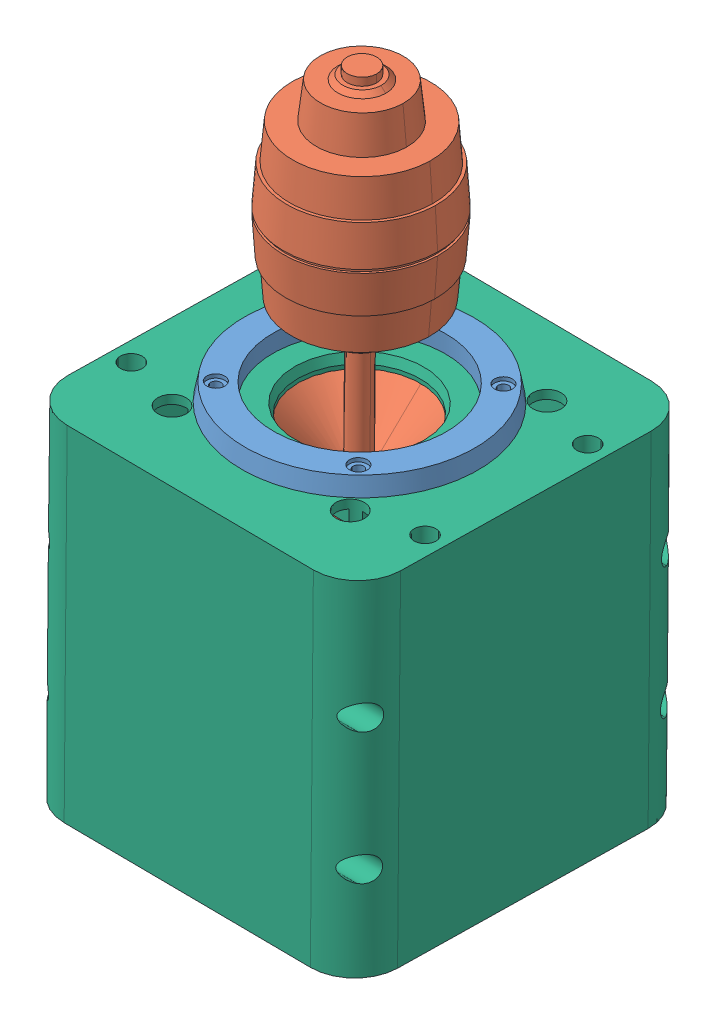
SolidWorks assembly Joystick control, configuration Default. Lengths in mm.
Overall size (77.67 146.17 78.62).
90 component instances, 26 part files, 9 mates.
Components (placement in the parent):
- D400B-M4-10KB 3-Axis Joystick with Button.STEP-1: D400B-M4-10KB 3-Axis Joystick with Button.STEP [Default] at (42.4495 -65.9811 -23.915) x (0.999962 0.000076 0.008726) z (-0.008727 0.008726 0.999924) size (76.37 95.5 76.37)
  - Mount Ring^D400B-M4-10KB 3-Axis Joystick with Button.STEP-1: Mount Ring^D400B-M4-10KB 3-Axis Joystick with Button.STEP [Default] at (0 28.75 0) x (0.707107 0 0.707107) z (-0.707107 0 0.707107) size (54 4 54)
  - Main^D400B-M4-10KB 3-Axis Joystick with Button.STEP-1: Main^D400B-M4-10KB 3-Axis Joystick with Button.STEP [Default] at origin size (59.55 95.5 49.55)
  - Seal^D400B-M4-10KB 3-Axis Joystick with Button.STEP-1: Seal^D400B-M4-10KB 3-Axis Joystick with Button.STEP [Default] at (0 25.75 0) x (0.707107 0 0.707107) z (-0.707107 0 0.707107) size (48.47 4 48.47) (hidden)
- remote_pcb.step-1: remote_pcb.step [Default] at (-56.1244 -87.3851 -127.4214) x (0.999962 0.000076 0.008726) z (0 0.999962 -0.008727) size (47.38 49.95 11.94)
  - PinHeader_1x04_P2.54mm_Vertical.step-1: PinHeader_1x04_P2.54mm_Vertical.step [Default] at (114.8 -120.23 1.63) x (-1 0 0) z (0 0 1) size (2.54 10.16 11.54)
    - SOLID.step-1: SOLID.step [Default] at origin size (2.54 10.16 11.54)
  - R_0402_1005Metric.step-1: R_0402_1005Metric.step [Default] at (89.4 -92.15 1.63) x (0 -1 0) z (0 0 1) size (1 0.5 0.35)
    - SOLID-0.step-1: SOLID-0.step [Default] at origin size (1 0.5 0.35)
  - JST_PH_S3B-PH-K_1x03_P2.00mm_Horizontal.step-1: JST_PH_S3B-PH-K_1x03_P2.00mm_Horizontal.step [Default] at (83.25 -107.15 1.63) x (0 -1 0) z (0 0 1) size (7.9 7.6 8.25)
    - SOLID-1.step-1: SOLID-1.step [Default] at origin size (7.9 7.6 8.25)
  - PinHeader_1x03_P2.54mm_Vertical.step-1: PinHeader_1x03_P2.54mm_Vertical.step [Default] at (92 -90.025 1.63) size (2.54 7.62 11.54)
    - SOLID-2.step-1: SOLID-2.step [Default] at origin size (2.54 7.62 11.54)
  - C_0402_1005Metric.step-1: C_0402_1005Metric.step [Default] at (105.05 -110.05 1.63) x (-1 0 0) z (0 0 1) size (1 0.5 0.5)
    - SOLID-3.step-1: SOLID-3.step [Default] at origin size (1 0.5 0.5)
  - R_0402_1005Metric.step-2: R_0402_1005Metric.step [Default] at (112.1 -90.4 1.63) x (0 1 0) z (0 0 1) size (1 0.5 0.35)
    - SOLID-0.step-1: SOLID-0.step [Default] at origin size (1 0.5 0.35)
  - PinHeader_1x04_P2.54mm_Vertical.step-2: PinHeader_1x04_P2.54mm_Vertical.step [Default] at (120.65 -120.28 1.63) x (-1 0 0) z (0 0 1) size (2.54 10.16 11.54)
    - SOLID.step-1: SOLID.step [Default] at origin size (2.54 10.16 11.54)
  - PinHeader_1x08_P2.54mm_Vertical.step-1: PinHeader_1x08_P2.54mm_Vertical.step [Default] at (105.275 -79.85 1.63) x (0 -1 0) z (0 0 1) size (2.54 20.32 11.54)
    - SOLID-4.step-1: SOLID-4.step [Default] at origin size (2.54 20.32 11.54)
  - L_1206_3216Metric.step-1: L_1206_3216Metric.step [Default] at (88.65 -97.75 1.63) x (0 1 0) z (0 0 1) size (3.2 1.6 1.6)
    - SOLID-5.step-1: SOLID-5.step [Default] at origin size (3.2 1.6 1.6)
  - R_0402_1005Metric.step-3: R_0402_1005Metric.step [Default] at (111.31 -107.5 1.63) x (0 -1 0) z (0 0 1) size (1 0.5 0.35)
    - SOLID-0.step-1: SOLID-0.step [Default] at origin size (1 0.5 0.35)
  - R_0402_1005Metric.step-4: R_0402_1005Metric.step [Default] at (90.81 -120.505 1.63) size (1 0.5 0.35)
    - SOLID-0.step-1: SOLID-0.step [Default] at origin size (1 0.5 0.35)
  - SW_CuK_JS202011AQN_DPDT_Angled.step-1: SW_CuK_JS202011AQN_DPDT_Angled.step [Default] at (118.175 -91.2005 1.63) x (0 1 0) z (0 0 1) size (9 5.6 6.5)
    - SOLID-6.step-1: SOLID-6.step [Default] at origin size (9 5.6 6.5)
  - SOT-23-6.step-1: SOT-23-6.step [Default] at (110.5 -86.85 1.63) size (2.8 2.9 1.55)
    - SOLID-7.step-1: SOLID-7.step [Default] at origin size (2.8 2.9 1.55)
  - C_1210_3225Metric.step-1: C_1210_3225Metric.step [Default] at (114.85 -89.35 1.63) x (0 -1 0) z (0 0 1) size (3.2 2.5 2.5)
    - SOLID-8.step-1: SOLID-8.step [Default] at origin size (3.2 2.5 2.5)
  - PinHeader_1x08_P2.54mm_Vertical.step-2: PinHeader_1x08_P2.54mm_Vertical.step [Default] at (96.02 -125.75 1.63) x (0 1 0) z (0 0 1) size (2.54 20.32 11.54)
    - SOLID-4.step-1: SOLID-4.step [Default] at origin size (2.54 20.32 11.54)
  - C_0402_1005Metric.step-2: C_0402_1005Metric.step [Default] at (90.2 -105.5 1.63) x (-1 0 0) z (0 0 1) size (1 0.5 0.5)
    - SOLID-3.step-1: SOLID-3.step [Default] at origin size (1 0.5 0.5)
  - C_0402_1005Metric.step-3: C_0402_1005Metric.step [Default] at (94.9 -105.2 1.63) x (0 -1 0) z (0 0 1) size (1 0.5 0.5)
    - SOLID-3.step-1: SOLID-3.step [Default] at origin size (1 0.5 0.5)
  - Crystal_SMD_3225-4Pin_3.2x2.5mm.step-1: Crystal_SMD_3225-4Pin_3.2x2.5mm.step [Default] at (92.2 -102.75 1.63) x (0 1 0) z (0 0 1) size (3.2 2.5 0.64)
    - SOLID-9.step-1: SOLID-9.step [Default] at origin size (3.2 2.5 0.64)
  - JST_PH_S2B-PH-K_1x02_P2.00mm_Horizontal.step-1: JST_PH_S2B-PH-K_1x02_P2.00mm_Horizontal.step [Default] at (83.3 -117.6 1.63) x (0 -1 0) z (0 0 1) size (5.9 7.6 8.25)
    - SOLID-10.step-1: SOLID-10.step [Default] at origin size (5.9 7.6 8.25)
  - L_Coilcraft_XAL5020-XXX.step-1: L_Coilcraft_XAL5020-XXX.step [Default] at (112.75 -81.2 1.63) x (-1 0 0) z (0 0 1) size (5.48 5.68 2)
    - COMPOUND.step-1: COMPOUND.step [Default] at origin size (5.48 5.68 2)
  - C_0402_1005Metric.step-4: C_0402_1005Metric.step [Default] at (107.5 -101.25 1.63) x (0 -1 0) z (0 0 1) size (1 0.5 0.5)
    - SOLID-3.step-1: SOLID-3.step [Default] at origin size (1 0.5 0.5)
  - LQFP-48_7x7mm_P0.5mm.step-1: LQFP-48_7x7mm_P0.5mm.step [Default] at (101.25 -104.25 1.63) size (9 9 1.5)
    - SOLID-11.step-1: SOLID-11.step [Default] at origin size (9 9 1.5)
  - R_0402_1005Metric.step-5: R_0402_1005Metric.step [Default] at (111.85 -104.2 1.63) x (0 -1 0) z (0 0 1) size (1 0.5 0.35)
    - SOLID-0.step-1: SOLID-0.step [Default] at origin size (1 0.5 0.35)
  - R_0402_1005Metric.step-6: R_0402_1005Metric.step [Default] at (111.31 -102 1.63) x (0 1 0) z (0 0 1) size (1 0.5 0.35)
    - SOLID-0.step-1: SOLID-0.step [Default] at origin size (1 0.5 0.35)
  - C_0402_1005Metric.step-5: C_0402_1005Metric.step [Default] at (93.6 -107.15 1.63) x (0 1 0) z (0 0 1) size (1 0.5 0.5)
    - SOLID-3.step-1: SOLID-3.step [Default] at origin size (1 0.5 0.5)
  - C_0402_1005Metric.step-6: C_0402_1005Metric.step [Default] at (96.25 -100.25 1.63) x (-1 0 0) z (0 0 1) size (1 0.5 0.5)
    - SOLID-3.step-1: SOLID-3.step [Default] at origin size (1 0.5 0.5)
  - C_0402_1005Metric.step-7: C_0402_1005Metric.step [Default] at (91.5 -99.75 1.63) size (1 0.5 0.5)
    - SOLID-3.step-1: SOLID-3.step [Default] at origin size (1 0.5 0.5)
  - JST_PH_S3B-PH-K_1x03_P2.00mm_Horizontal.step-2: JST_PH_S3B-PH-K_1x03_P2.00mm_Horizontal.step [Default] at (83.25 -96.65 1.63) x (0 -1 0) z (0 0 1) size (7.9 7.6 8.25)
    - SOLID-1.step-1: SOLID-1.step [Default] at origin size (7.9 7.6 8.25)
  - C_0402_1005Metric.step-8: C_0402_1005Metric.step [Default] at (89.7 -101.75 1.63) x (0 -1 0) z (0 0 1) size (1 0.5 0.5)
    - SOLID-3.step-1: SOLID-3.step [Default] at origin size (1 0.5 0.5)
  - JST_PH_S3B-PH-K_1x03_P2.00mm_Horizontal.step-3: JST_PH_S3B-PH-K_1x03_P2.00mm_Horizontal.step [Default] at (83.25 -86.4 1.63) x (0 -1 0) z (0 0 1) size (7.9 7.6 8.25)
    - SOLID-1.step-1: SOLID-1.step [Default] at origin size (7.9 7.6 8.25)
  - PinHeader_1x03_P2.54mm_Vertical.step-2: PinHeader_1x03_P2.54mm_Vertical.step [Default] at (91.45 -125.7 1.63) x (0 -1 0) z (0 0 1) size (2.54 7.62 11.54)
    - SOLID-2.step-1: SOLID-2.step [Default] at origin size (2.54 7.62 11.54)
  - C_0805_2012Metric.step-1: C_0805_2012Metric.step [Default] at (95 -98.5 1.63) x (-1 0 0) z (0 0 1) size (2 1.25 1.25)
    - SOLID-12.step-1: SOLID-12.step [Default] at origin size (2 1.25 1.25)
  - R_0402_1005Metric.step-7: R_0402_1005Metric.step [Default] at (110.35 -90.4 1.63) x (0 -1 0) z (0 0 1) size (1 0.5 0.35)
    - SOLID-0.step-1: SOLID-0.step [Default] at origin size (1 0.5 0.35)
  - LED_0603_1608Metric.step-1: LED_0603_1608Metric.step [Default] at (88.65 -121.45 1.63) x (0 -1 0) z (0 0 1) size (1.6 0.8 1.1)
    - SOLID-13.step-1: SOLID-13.step [Default] at origin size (1.6 0.8 1.1)
  - PinHeader_1x02_P2.54mm_Vertical.step-1: PinHeader_1x02_P2.54mm_Vertical.step [Default] at (120.65 -97 1.63) x (0 -1 0) z (0 0 1) size (2.54 5.08 11.54)
    - SOLID-14.step-1: SOLID-14.step [Default] at origin size (2.54 5.08 11.54)
  - SOT-223.step-1: SOT-223.step [Default] at (99.05 -91.9 1.63) x (-1 0 0) z (0 0 1) size (7 6.5 1.7)
    - SOLID-15.step-1: SOLID-15.step [Default] at origin size (7 6.5 1.7)
  - SW_Tactile_SPST_NO_Straight_CK_PTS636Sx25SMTRLFS.step-1: SW_Tactile_SPST_NO_Straight_CK_PTS636Sx25SMTRLFS.step [Default] at (89.5 -114.35 1.63) x (0 1 0) z (0 0 1) size (8 3.7 2.55)
    - COMPOUND-16.step-1: COMPOUND-16.step [Default] at origin size (8 3.7 2.55)
  - C_0402_1005Metric.step-9: C_0402_1005Metric.step [Default] at (98.25 -98.25 1.63) size (1 0.5 0.5)
    - SOLID-3.step-1: SOLID-3.step [Default] at origin size (1 0.5 0.5)
  - R_0402_1005Metric.step-8: R_0402_1005Metric.step [Default] at (108.6 -90.4 1.63) x (0 1 0) z (0 0 1) size (1 0.5 0.35)
    - SOLID-0.step-1: SOLID-0.step [Default] at origin size (1 0.5 0.35)
  - C_0402_1005Metric.step-10: C_0402_1005Metric.step [Default] at (92.2 -107.15 1.63) x (0 1 0) z (0 0 1) size (1 0.5 0.5)
    - SOLID-3.step-1: SOLID-3.step [Default] at origin size (1 0.5 0.5)
  - D_SOD-123.step-1: D_SOD-123.step [Default] at (106.55 -87.55 1.63) x (0 1 0) z (0 0 1) size (3.8 1.6 1.25)
    - SOLID-17.step-1: SOLID-17.step [Default] at origin size (3.8 1.6 1.25)
  - remote_pcb PCB.step-1: remote_pcb PCB.step [Default] at origin size (46.45 49.95 1.58)
- Controller box-1: Controller box [Default] at (42.4495 -115.9792 -23.4787) x (-0.008727 0.008726 0.999924) z (-0.999962 -0.000076 -0.008726) size (77 78.64 77)
- AABattery Holder.stp-1: AABattery Holder.stp [Default] at (59.5248 -99.8544 -60.8183) x (0.999962 0.000076 0.008726) z (0 -0.999962 0.008727) size (31.51 57.98 19)
Mates (geometry in assembly coordinates):
- Concentric1: concentric aligned: cylinder of remote_pcb.step-1/remote_pcb PCB.step-1 through (22.0206 -87.4671 -46.2825) axis (0 0.999962 -0.008727) radius 1.05; circle of Controller box-1
- Concentric2: concentric aligned: circle of remote_pcb.step-1/remote_pcb PCB.step-1; circle of Controller box-1
- Coincident3: coincident anti-aligned: plane of remote_pcb.step-1/remote_pcb PCB.step-1 through (42.4495 -86.4803 -23.7362) normal (0 -0.999962 0.008727); circle of Controller box-1
- Coincident4: coincident anti-aligned: plane of D400B-M4-10KB 3-Axis Joystick with Button.STEP-1/Main^D400B-M4-10KB 3-Axis Joystick with Button.STEP-1 through (42.4495 -65.9811 -23.915) normal (0 -0.999962 0.008727); plane of Controller box-1 through (42.4495 -65.9811 -23.915) normal (0 0.999962 -0.008727)
- Coincident5: coincident aligned: plane of D400B-M4-10KB 3-Axis Joystick with Button.STEP-1 through (42.4495 -65.9811 -23.915) normal (-0.008727 0.008726 0.999924); plane of Controller box-1 through (42.4495 -115.9792 -23.4787) normal (-0.008727 0.008726 0.999924)
- Coincident6: coincident anti-aligned: plane of D400B-M4-10KB 3-Axis Joystick with Button.STEP-1 through (42.4495 -65.9811 -23.915) normal (0.999962 0.000076 0.008726); plane of Controller box-1 through (42.4495 -115.9792 -23.4787) normal (-0.999962 -0.000076 -0.008726)
- Distance1: distance = 0.75 mm anti-aligned: plane of Controller box-1 through (58.6784 -37.0704 6.9766) normal (-0.999962 -0.000076 -0.008726); plane of AABattery Holder.stp-1 through (58.431 -93.2109 -50.135) normal (0.999962 0.000076 0.008726)
- Distance2: distance = 2.095 mm anti-aligned: plane of Controller box-1 through (4.2215 -37.6156 -55.4986) normal (-0.008727 0.008726 0.999924); plane of AABattery Holder.stp-1 through (28.2023 -93.2334 -52.7088) normal (0.008727 -0.008726 -0.999924)
- Coincident9: coincident anti-aligned: plane of Controller box-1 through (42.4495 -91.9801 -23.6882) normal (0 -0.999962 0.008727); plane of AABattery Holder.stp-1 through (56.7098 -91.7398 3.8413) normal (0 0.999962 -0.008727)
